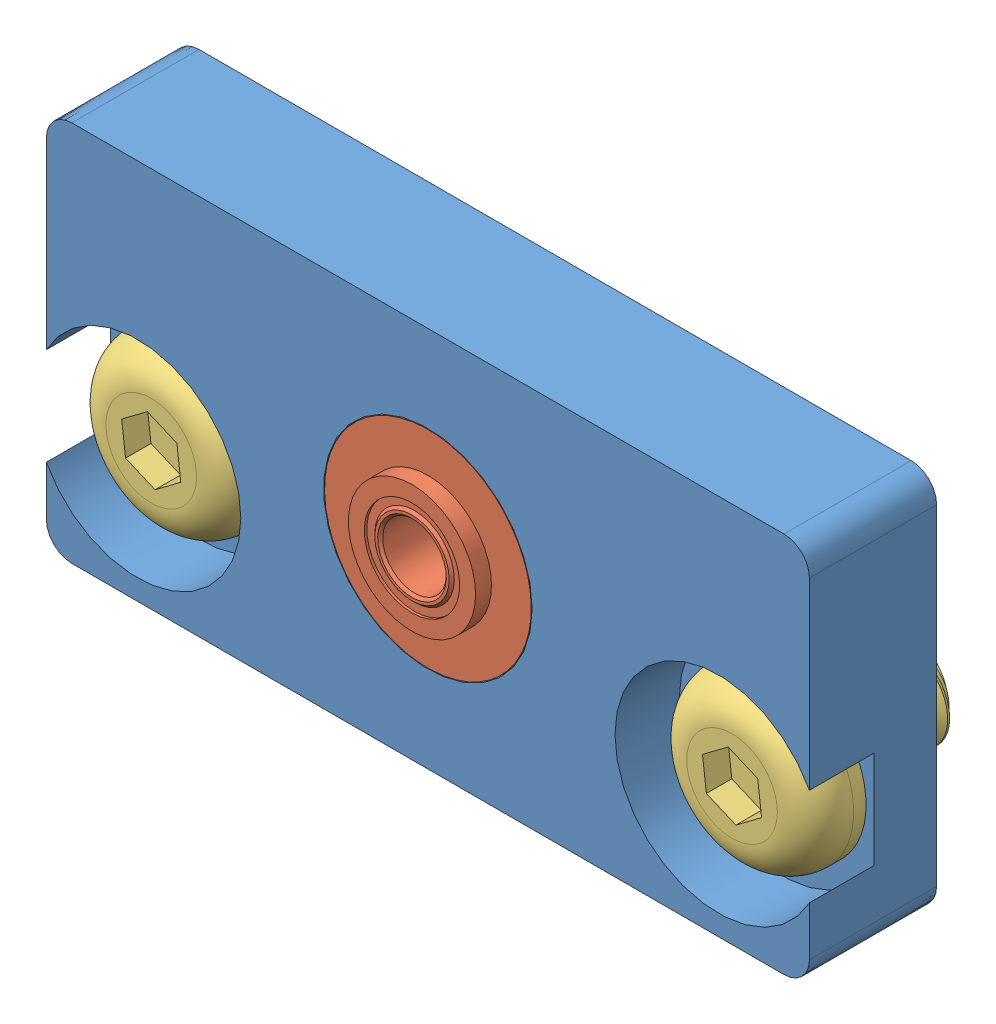
SolidWorks assembly bearing_mount_assembly, configuration Default. Lengths in mm.
Overall size (82.55 41.41 21.2).
4 component instances, 3 part files, 6 mates.
Components (placement in the parent):
- bearing_mount-1: bearing_mount [Default] at (16.918 37.8476 59.5248) size (82.55 41.41 12.7)
- flanged_bearing-1: flanged_bearing [Default] at (16.918 37.8476 72.2248) x (-0.923728 -0.383049 0) z (0 0 -1) size (20.64 20.64 9.53)
- S-375-050-BTN-H-SS-1: S-375-050-BTN-H-SS [Default] at (-12.082 31.1396 65.7986) size (16.66 16.66 18.24)
- S-375-050-BTN-H-SS-2: S-375-050-BTN-H-SS [Default] at (45.918 31.1396 65.7986) size (16.66 16.66 18.24)
Mates (geometry in assembly coordinates):
- Coincident1: coincident anti-aligned: plane of bearing_mount-1 through (16.918 37.8476 70.6373) normal (0 0 1); plane of flanged_bearing-1 through (16.918 37.8476 70.6373) normal (0 0 -1)
- Concentric1: concentric anti-aligned: circle of bearing_mount-1; circle of flanged_bearing-1
- Concentric2: concentric aligned: circle of bearing_mount-1; circle of S-375-050-BTN-H-SS-1
- Coincident2: coincident anti-aligned: plane of bearing_mount-1 through (-7.0401 31.1396 65.7986) normal (0 0 1); plane of S-375-050-BTN-H-SS-1 through (-12.082 31.1396 65.7986) normal (0 0 -1)
- Concentric3: concentric aligned: circle of bearing_mount-1; circle of S-375-050-BTN-H-SS-2
- Coincident3: coincident anti-aligned: plane of bearing_mount-1 through (50.9599 31.1396 65.7986) normal (0 0 1); plane of S-375-050-BTN-H-SS-2 through (45.918 31.1396 65.7986) normal (0 0 -1)
